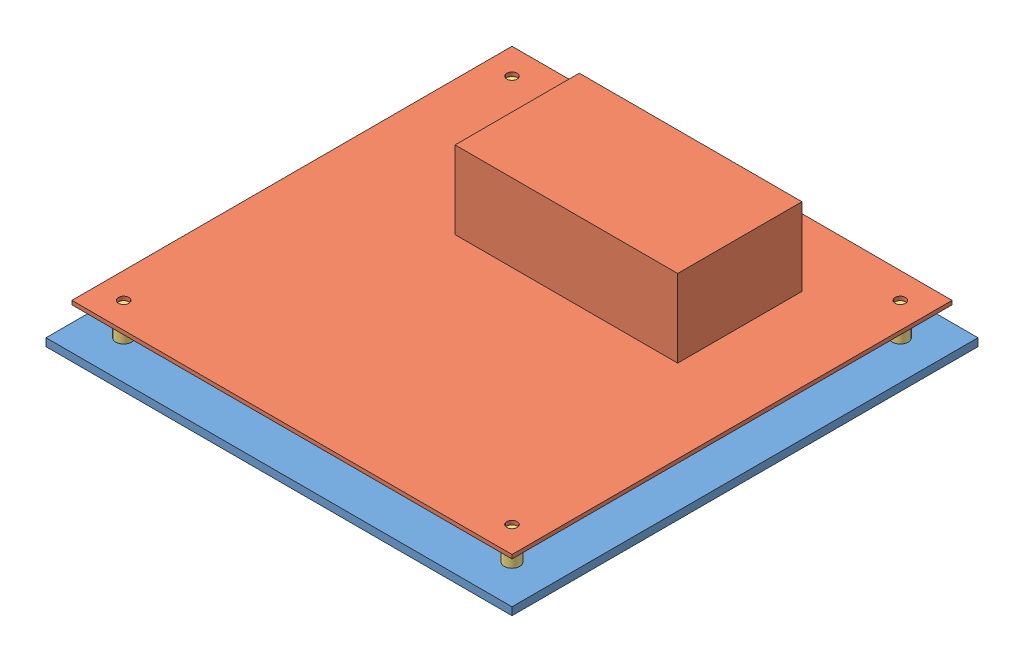
SolidWorks assembly Jetson H, configuration Default. Lengths in mm.
Overall size (180 45.5 180).
6 component instances, 3 part files, 11 mates.
Components (placement in the parent):
- Base-1: Base [Default] at (67.0689 90.6709 139.4266) size (180 3 180)
- Board-1: Board [Default] at (67.0689 104.6709 139.4266) size (170 31.5 170)
- Separador-1: Separador [Default] at (-7.9311 93.6709 214.4266) x (0.99477 0 -0.102141) z (0.102141 0 0.99477) size (6 11 6)
- Separador-2: Separador [Default] at (142.0689 93.6709 64.4266) size (6 11 6)
- Separador-3: Separador [Default] at (142.0689 93.6709 214.4266) size (6 11 6)
- Separador-4: Separador [Default] at (-7.9311 93.6709 64.4266) size (6 11 6)
Mates (geometry in assembly coordinates):
- Concentric1: concentric aligned: circle of Base-1; circle of Separador-1
- Concentric2: concentric aligned: circle of Base-1; circle of Separador-4
- Concentric3: concentric aligned: circle of Base-1; circle of Separador-3
- Concentric4: concentric aligned: circle of Base-1; circle of Separador-2
- Concentric6: concentric aligned: circle of Board-1; circle of Separador-1
- Concentric7: concentric aligned: circle of Board-1; circle of Separador-3
- Coincident1: coincident anti-aligned: plane of Base-1 through (67.0689 93.6709 139.4266) normal (0 1 0); plane of Separador-1 through (-7.9311 93.6709 214.4266) normal (0 -1 0)
- Coincident2: coincident anti-aligned: plane of Base-1 through (67.0689 93.6709 139.4266) normal (0 1 0); plane of Separador-4 through (-7.9311 93.6709 64.4266) normal (0 -1 0)
- Coincident3: coincident anti-aligned: plane of Base-1 through (67.0689 93.6709 139.4266) normal (0 1 0); plane of Separador-2 through (142.0689 93.6709 64.4266) normal (0 -1 0)
- Coincident4: coincident anti-aligned: plane of Base-1 through (67.0689 93.6709 139.4266) normal (0 1 0); plane of Separador-3 through (142.0689 93.6709 214.4266) normal (0 -1 0)
- Coincident5: coincident anti-aligned: plane of Board-1 through (67.0689 104.6709 139.4266) normal (0 -1 0); plane of Separador-1 through (-7.9311 104.6709 214.4266) normal (0 1 0)
